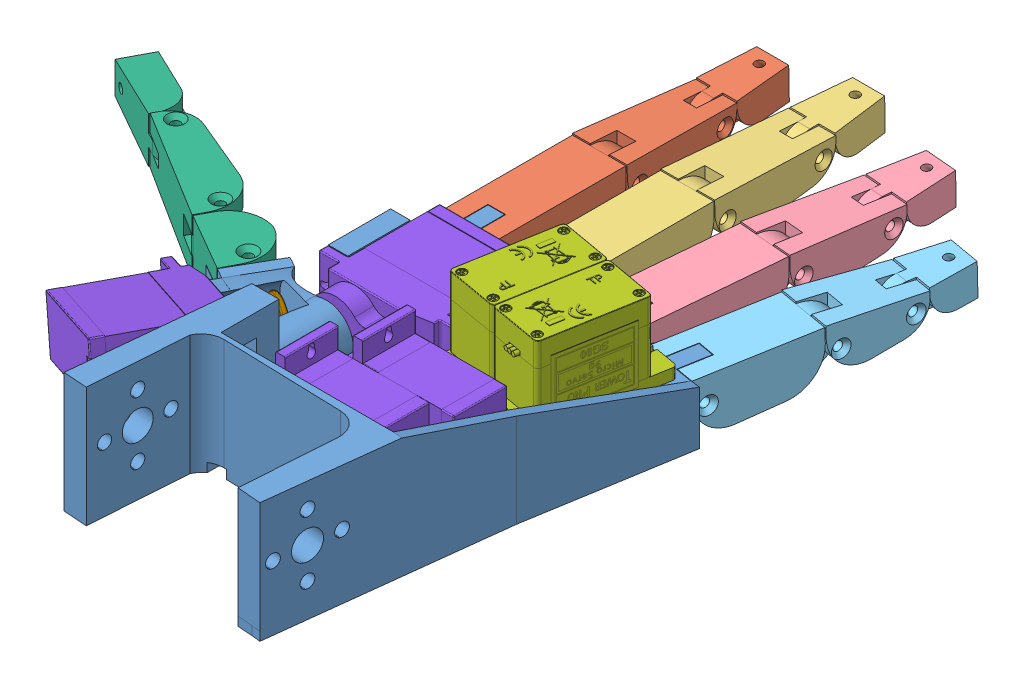
SolidWorks assembly hand assem, configuration Default. Lengths in mm.
Overall size (141.23 34.46 165.82).
18 component instances, 10 part files, 46 mates.
Components (placement in the parent):
- Palm-1: Palm [Default] at origin size (85.11 27 98.66)
- Index_finger-2: Index_finger [Default] at (0 6 0) x (0 0.019612 -0.999808) z (1 0 0) size (69.04 11.96 12.34)
- Middle_finger-2: Middle_finger [Default] at (16.7702 6 0) x (0 0.01786 -0.99984) z (1 0 0) size (73.84 11.96 12.16)
- Ring_finger-1: Ring_finger [Default] at (33.5031 6 0.5) x (0.087141 0.018522 -0.996024) z (0.996195 0 0.087156) size (68.44 11.96 12.18)
- Pinky_finger-1: Pinky_finger [Default] at (50.0331 6 3.5) x (0.173603 0.022733 -0.984553) z (0.984808 0 0.173648) size (57.04 11.95 12.23)
- THUMNB-1: THUMNB [Default] at (-19.8 6 32.1962) x (-0.884628 0 -0.466298) z (0 1 0) size (63.04 11.91 12.14)
- SG90 - Micro Servo 9g - Tower Pro.1-1: SG90 - Micro Servo 9g - Tower Pro.1 [Peça] at (34.091 21.3 23.0791) x (-0.173648 0 0.984808) z (0.984808 0 0.173648) size (32.1 29.95 12.4)
- SERVO MG92B-1: SERVO MG92B [Predeterminado] at (9.845 12.03 7.5) x (-1 0 0) z (0 1 0) size (31.69 33.93 12.06)
- SERVO MG92B-2: SERVO MG92B [Predeterminado] at (-21.8858 10.9905 70.397) x (0.866195 0.234594 0.441216) z (-0.203429 0.97202 -0.11745) size (31.69 33.93 12.06)
- SG90 - Micro Servo 9g - Tower Pro.1-2: SG90 - Micro Servo 9g - Tower Pro.1 [Peça] at (46.1057 21.3 25.1976) x (0.173648 0 -0.984808) z (-0.984808 0 -0.173648) size (32.1 29.95 12.4)
- SERVO MG92B-3: SERVO MG92B [Predeterminado] at (42.6589 13.335 59.8384) x (0 -1 0) z (0 0 -1) size (31.69 33.93 12.06)
- SERVO MG92B-4: SERVO MG92B [Predeterminado] at (48.1589 13.335 47.9584) x (0 -1 0) z (0 0 -1) size (31.69 33.93 12.06)
- pulley_20T-1: pulley_20T [Default] at (14.3089 8.03 47.9584) x (0 -1 0) z (0 0 1) size (11.5 2.8 12.87)
- thumb pin-1: thumb pin [Default] at (4.54 12.03 48.095) x (-0.958856 -0.283892 0) z (-0.283892 0.958856 0) size (3.7 10 3.7)
- pulley_20T-3: pulley_20T [Default] at (-3.1186 11.8631 45.113) x (-0.87826 0.154197 -0.45264) z (-0.142609 -0.987967 -0.059859) size (11.5 2.8 12.87)
- pulley_20T-4: pulley_20T [Default] at (11.6089 8.03 59.8384) x (0 0.837169 -0.546944) z (0 0.546944 0.837169) size (11.5 2.8 12.87)
- pulley_20T-5: pulley_20T [Default] at (45.2114 4.8 30.2694) x (-0.837169 0 -0.546944) z (-0.546944 0 0.837169) size (11.5 2.8 12.87)
- pulley_20T-6: pulley_20T [Default] at (34.9853 4.8 18.0074) x (-0.837169 0 -0.546944) z (-0.546944 0 0.837169) size (11.5 2.8 12.87)
Mates (geometry in assembly coordinates):
- Coincident1: coordinate: point of Palm-1
- Concentric1: concentric aligned: cylinder of Palm-1 through (6 6 0) axis (-1 0 0) radius 1; cylinder of Index_finger-2 through (6.1691 6 0) axis (-1 0 0) radius 1
- Coincident2: coincident: plane of Palm-1 through (6 12 6) normal (0 1 0); point of Index_finger-2
- Concentric2: concentric anti-aligned: cylinder of Palm-1 through (22.7702 6 0) axis (-1 0 0) radius 1; cylinder of Middle_finger-2 through (10.6925 6 0) axis (1 0 0) radius 0.8
- Coincident4: coincident: plane of Palm-1 through (6 12 6) normal (0 1 0); point of Middle_finger-2
- Concentric3: concentric anti-aligned: cylinder of Palm-1 through (39.4803 6 1.0229) axis (-0.996195 0 -0.087156) radius 1; cylinder of Ring_finger-1 through (27.4364 6 -0.0308) axis (0.996195 0 0.087156) radius 0.8
- Coincident5: coincident: plane of Palm-1 through (6 12 6) normal (0 1 0); point of Ring_finger-1
- Concentric4: concentric aligned: cylinder of Pinky_finger-1 through (56.0552 6 4.5619) axis (-0.984808 0 -0.173648) radius 1; cylinder of Palm-1 through (55.9419 6 4.5419) axis (-0.984808 0 -0.173648) radius 1
- Coincident7: coincident: plane of Palm-1 through (6 12 6) normal (0 1 0); point of Pinky_finger-1
- Width5: width anti-aligned: plane of Palm-1 through (0 12 0) normal (0 1 0); plane of Palm-1 through (0 0 0) normal (0 -1 0); plane of THUMNB-1 through (-13.4077 4 28.6474) normal (0 1 0); plane of THUMNB-1 through (-13.4077 8 28.6474) normal (0 -1 0)
- Concentric5: concentric anti-aligned: cylinder of Palm-1 through (-19.8 12 32.1962) axis (0 -1 0) radius 1; cylinder of THUMNB-1 through (-19.8 -0.0719 32.1962) axis (0 1 0) radius 0.8
- Coincident11: coincident anti-aligned: plane of SERVO MG92B-1 through (21.18 6 32.65) normal (0 -1 0)
- Coincident12: coincident: plane of Palm-1 through (-27.9962 12 34.3923) normal (-0.5 0 0.866025); point of THUMNB-1
- Coincident15: coincident anti-aligned: plane of SG90 - Micro Servo 9g - Tower Pro.1-2 through (45.2114 2 30.2694) normal (0 -1 0)
- Coincident16: coincident anti-aligned: plane of SG90 - Micro Servo 9g - Tower Pro.1-1 through (34.9853 2 18.0074) normal (0 -1 0)
- Coincident17: coincident anti-aligned: plane of SG90 - Micro Servo 9g - Tower Pro.1-1 through (38.2924 31.85 34.3804) normal (0.984808 0 0.173648); plane of SG90 - Micro Servo 9g - Tower Pro.1-2 through (41.9043 31.85 13.8964) normal (-0.984808 0 -0.173648)
- Coincident18: coincident aligned: plane of SG90 - Micro Servo 9g - Tower Pro.1-1 through (37.3077 16.15 35.0699) normal (-0.173648 0 0.984808); plane of SG90 - Micro Servo 9g - Tower Pro.1-2 through (38.9819 16.15 35.3651) normal (-0.173648 0 0.984808)
- Coincident19: coincident anti-aligned: plane of SERVO MG92B-3 through (42.6589 13.335 53.9584) normal (0 0 -1); plane of SERVO MG92B-4 through (48.1589 13.335 53.9584) normal (0 0 1)
- Coincident20: coincident aligned: plane of SERVO MG92B-3 through (25.5493 24.67 65.8384) normal (0 1 0); plane of SERVO MG92B-4 through (31.0493 24.67 53.9584) normal (0 1 0)
- Distance5: distance = 2 mm anti-aligned: plane of SERVO MG92B-3 through (39.9041 2 65.8384) normal (0 -1 0)
- Tangent1: tangent anti-aligned: cylinder of SG90 - Micro Servo 9g - Tower Pro.1-2 through (48.6365 13.65 41.0784) axis (0 1 0) radius 0.85; plane of SERVO MG92B-4 through (23.0089 24.67 41.9284) normal (0 0 -1)
- Distance2: distance = 5.5 mm aligned: plane of SERVO MG92B-3 through (42.6589 13.335 59.8384) normal (1 0 0); plane of SERVO MG92B-4 through (48.1589 13.335 47.9584) normal (1 0 0)
- Parallel2: parallel anti-aligned: plane of Palm-1 through (6 0 6) normal (0 0 1); plane of SERVO MG92B-1 through (9.845 12.03 7.5) normal (0 0 -1)
- Distance3: distance = 1.5 mm anti-aligned: plane of SERVO MG92B-1 through (9.845 12.03 7.5) normal (0 0 -1); plane of Palm-1 through (6 0 6) normal (0 0 1)
- Coincident24: coincident aligned: plane of Palm-1 through (-6 0 0) normal (-1 0 0); plane of SERVO MG92B-1 through (-6 12.03 7.5) normal (-1 0 0)
- Coincident25: coincident anti-aligned: plane of Palm-1 through (54.9 0 10.4507) normal (-0.173648 0 0.984808); plane of SG90 - Micro Servo 9g - Tower Pro.1-2 through (43.7225 13.65 8.4798) normal (0.173648 0 -0.984808)
- Parallel3: parallel anti-aligned: plane of Palm-1 through (6 0 6) normal (0 0 1); plane of SERVO MG92B-4 through (48.1589 13.335 42.0784) normal (0 0 -1)
- Coincident28: coincident anti-aligned: plane of Palm-1 through (-21.7173 0 42.2191) normal (-0.45399 0 0.891007); plane of SERVO MG92B-2 through (-10.4067 10.6892 48.0215) normal (0.456424 -0.011978 -0.889682)
- Parallel6: parallel aligned: plane of Palm-1 through (-19.3538 0 43.4234) normal (0.203429 -0.97202 0.11745); plane of SERVO MG92B-2 through (-18.9983 2.1688 43.7285) normal (0.203429 -0.97202 0.11745)
- Distance4: distance = 2 mm aligned: plane of SERVO MG92B-2 through (-18.9983 2.1688 43.7285) normal (0.203429 -0.97202 0.11745); plane of Palm-1 through (-19.3538 0 43.4234) normal (0.203429 -0.97202 0.11745)
- Coincident33: coincident: plane of Palm-1 through (-21.7173 0 42.2191) normal (-0.45399 0 0.891007); point of SERVO MG92B-2
- Coincident34: coincident: point of Palm-1; plane of SERVO MG92B-2 through (-12.1325 -0.9223 47.2925) normal (0.292829 -0.054065 -0.954635)
- Coincident35: coincident: point of Palm-1; plane of SERVO MG92B-2 through (-12.1325 -0.9223 47.2925) normal (0.292829 -0.054065 -0.954635)
- Coincident37: coincident: plane of Palm-1 through (43.3599 100.3935 94.6395) normal (-0.993187 0 -0.116532); line of SERVO MG92B-4 through (48.1589 24.42 53.7384) axis (0 -1 0)
- Concentric7: concentric anti-aligned: cylinder of Palm-1 through (4.54 12.03 48.4281) axis (0 0 1) radius 1.65; cone of thumb pin-1 through (4.54 12.03 48.095) axis (0 0 -1)
- Coincident39: coincident aligned: plane of Palm-1 through (7.965 18.06 58.095) normal (0 0 1); plane of thumb pin-1 through (4.54 12.03 58.095) normal (0 0 1)
- Coincident43: coincident anti-aligned: plane of SERVO MG92B-4 through (17.1089 8.03 47.9584) normal (-1 0 0); plane of pulley_20T-1 through (17.1089 8.03 50.3584) normal (1 0 0)
- Concentric8: concentric aligned: cylinder of SERVO MG92B-4 through (17.1089 8.03 47.9584) axis (-1 0 0) radius 1.925; circle of pulley_20T-1
- Coincident44: coincident anti-aligned: plane of SERVO MG92B-3 through (11.6089 8.03 59.8384) normal (-1 0 0); plane of pulley_20T-4 through (11.6089 10.9015 64.2335) normal (1 0 0)
- Concentric9: concentric anti-aligned: circle of SERVO MG92B-3; circle of pulley_20T-4
- Concentric10: concentric anti-aligned: circle of SERVO MG92B-2; circle of pulley_20T-3
- Coincident45: coincident anti-aligned: plane of SERVO MG92B-2 through (-3.1186 11.8631 45.113) normal (0.456424 -0.011978 -0.889682); plane of pulley_20T-3 through (-3.8673 6.6763 44.7987) normal (-0.456424 0.011978 0.889682)
- Concentric11: concentric anti-aligned: circle of SG90 - Micro Servo 9g - Tower Pro.1-2; circle of pulley_20T-5
- Coincident46: coincident aligned: plane of SG90 - Micro Servo 9g - Tower Pro.1-2 through (45.2114 2 30.2694) normal (0 -1 0); plane of pulley_20T-5 through (43.8987 2 32.2786) normal (0 -1 0)
- Coincident47: coincident aligned: plane of SG90 - Micro Servo 9g - Tower Pro.1-1 through (34.9853 2 18.0074) normal (0 -1 0); plane of pulley_20T-6 through (33.6726 2 20.0166) normal (0 -1 0)
- Concentric12: concentric anti-aligned: circle of SG90 - Micro Servo 9g - Tower Pro.1-1; circle of pulley_20T-6
